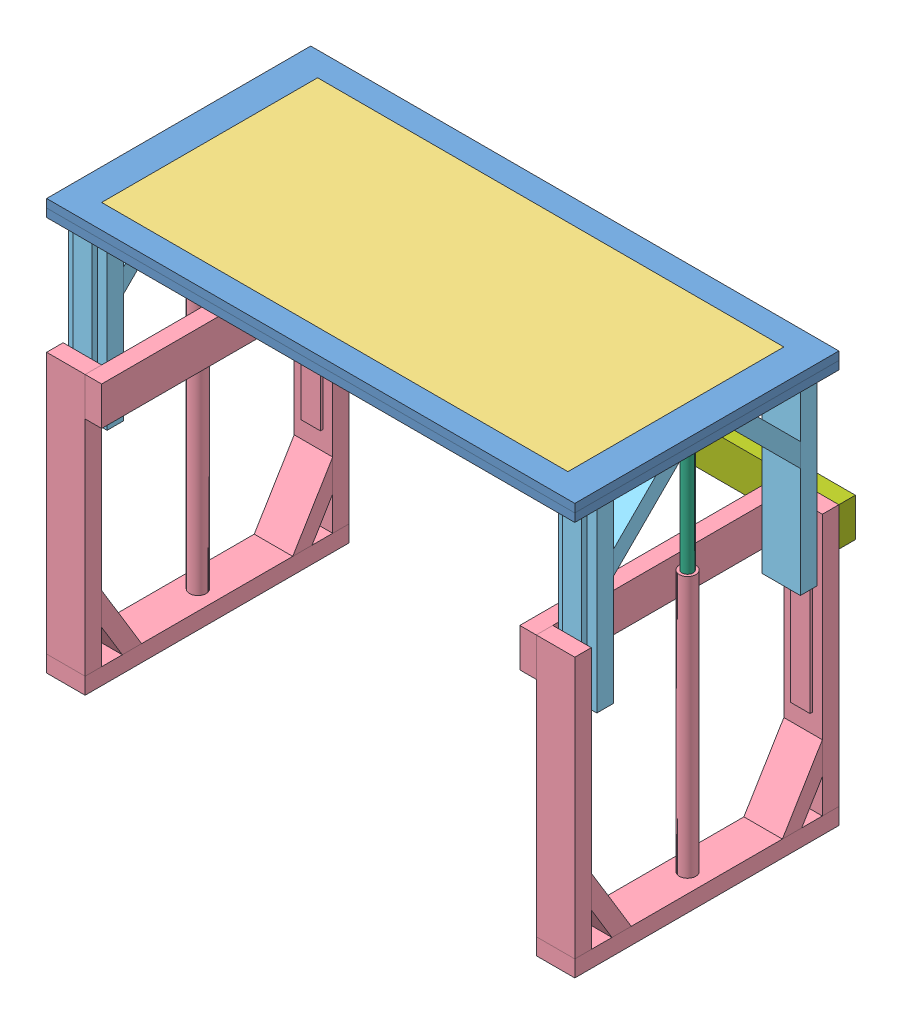
SolidWorks assembly desktron, configuration Default. Lengths in mm.
Overall size (1219.2 948.76 647.7).
12 component instances, 7 part files, 20 mates.
Components (placement in the parent):
- tabletop-2: tabletop [Default] at (0 910.6604 0) size (1219.2 38.1 609.6)
- mirror-2: mirror [Default] at (0 923.3604 0) size (977.9 6.35 431.8)
- window-1: window [Default] at (0 942.4104 0) size (1076.33 6.35 498.48)
- side-1: side [Default] at (-520.7 641.35 0) size (127 641.35 609.6)
- side-2: side [Default] at (520.7 641.35 0) x (-1 0 0) z (0 0 -1) size (127 641.35 609.6)
- slider-top-1: slider-top [Default] at (-609.6 910.6604 234.95) size (88.9 406.4 203.2)
- slider-top-2: slider-top [Default] at (-520.7 910.6604 -234.95) x (-1 0 0) z (0 0 -1) size (88.9 406.4 203.2)
- slider-top-3: slider-top [Default] at (520.7 910.6604 234.95) size (88.9 406.4 203.2)
- slider-top-4: slider-top [Default] at (609.6 910.6604 -234.95) x (-1 0 0) z (0 0 -1) size (88.9 406.4 203.2)
- Actuator_Slide^desktron-2: Actuator_Slide^desktron [Default] at (0 910.6604 0) x (-1 0 0) z (0 -1 0) size (25.4 25.4 406.4) (virtual)
- Actuator_Slide^desktron-3: Actuator_Slide^desktron [Default] at (0 504.2604 0) x (1 0 0) z (0 1 0) size (25.4 25.4 406.4) (virtual)
- Back_Brace^desktron-3: Back_Brace^desktron [Default] at (520.7 641.35 -304.8) x (-1 0 0) z (0 0 -1) size (1219.2 88.9 38.1) (virtual)
Mates (geometry in assembly coordinates):
- Coincident1: coincident anti-aligned: plane of tabletop-2 through (488.95 923.3604 215.9) normal (0 0 -1); plane of mirror-2 through (488.95 929.7104 215.9) normal (0 0 1)
- Coincident2: coincident anti-aligned: plane of tabletop-2 through (-488.95 923.3604 215.9) normal (1 0 0); plane of mirror-2 through (-488.95 929.7104 215.9) normal (-1 0 0)
- Coincident6: coincident anti-aligned: plane of tabletop-2 through (0 923.3604 0) normal (0 1 0); plane of mirror-2 through (0 923.3604 0) normal (0 -1 0)
- Coincident7: coincident anti-aligned: plane of tabletop-2 through (-538.1625 942.4104 249.2375) normal (1 0 0); plane of window-1 through (-538.1625 948.7604 249.2375) normal (-1 0 0)
- Coincident8: coincident anti-aligned: plane of tabletop-2 through (538.1625 942.4104 -249.2375) normal (0 0 1); plane of window-1 through (538.1625 948.7604 -249.2375) normal (0 0 -1)
- Coincident10: coincident anti-aligned: plane of tabletop-2 through (0 942.4104 0) normal (0 1 0); plane of window-1 through (0 942.4104 0) normal (0 -1 0)
- Coincident11: coincident aligned: plane of tabletop-2 through (-609.6 929.7104 304.8) normal (0 0 1); plane of side-1 through (-609.6 641.35 304.8) normal (0 0 1)
- Coincident15: coincident aligned: plane of tabletop-2 through (-609.6 929.7104 304.8) normal (-1 0 0); plane of side-1 through (-609.6 641.35 0) normal (-1 0 0)
- Coincident16: coincident anti-aligned: plane of side-1 through (-520.7 641.35 0) normal (-1 0 0); plane of slider-top-1 through (-520.7 910.6604 234.95) normal (1 0 0)
- Coincident17: coincident anti-aligned: plane of side-1 through (-609.6 641.35 266.7) normal (0 0 -1); plane of slider-top-1 through (-609.6 910.6604 266.7) normal (0 0 1)
- Coincident18: coincident anti-aligned: plane of tabletop-2 through (0 910.6604 0) normal (0 -1 0); plane of slider-top-1 through (-520.7 910.6604 254) normal (0 1 0)
- InPlace2: in place: plane of assembly through (0 0 0) normal (0 -1 0); plane of ? through (0 0 0) normal (0 -1 0); moOrthogonalPlaneRef_w of assembly through (0 0 0) normal (0 -1 0); unknown of ?; plane of assembly through (0 0 0) normal (0 -1 0); line of ? through (55 -55 0) axis (0 0 -1); plane of tabletop-2 through (0 910.6604 0) normal (0 -1 0); unknown of Actuator_Slide^desktron-2
- Coincident22: coincident aligned: plane of tabletop-2; plane of Actuator_Slide^desktron-2
- Coincident23: coincident aligned: moOrthogonalPlaneRef_w of tabletop-2 through (0 910.6604 0) normal (0 0 -1); plane of Actuator_Slide^desktron-2
- Coincident24: coincident anti-aligned: moOrthogonalPlaneRef_w of tabletop-2 through (0 910.6604 0) normal (1 0 0); plane of Actuator_Slide^desktron-2
- Coincident25: coincident anti-aligned: plane of assembly through (0 0 0) normal (0 1 0); plane of side-1 through (-520.7 0 0) normal (0 -1 0)
- InPlace3: in place: plane of side-2 through (609.6 641.35 -304.8) normal (0 0 -1); plane of ? through (0 0 -304.8) normal (0 0 -1); plane of side-2 through (609.6 641.35 -304.8) normal (0 0 -1); unknown of ?; plane of side-2 through (609.6 641.35 -304.8) normal (0 0 -1); plane of ? through (0 0 -304.8) normal (-1 0 0); plane of side-2 through (609.6 641.35 -304.8) normal (0 0 -1); unknown of Back_Brace^desktron-3
- Coincident26: coincident aligned: plane of side-2; plane of Back_Brace^desktron-3
- Coincident27: coincident aligned: moOrthogonalPlaneRef_w of side-2 through (520.7 641.35 -304.8) normal (0 1 0); plane of Back_Brace^desktron-3
- Coincident28: coincident anti-aligned: moOrthogonalPlaneRef_w of side-2 through (520.7 641.35 -304.8) normal (1 0 0); plane of Back_Brace^desktron-3 through (520.7 641.35 -304.8) normal (-1 0 0)
